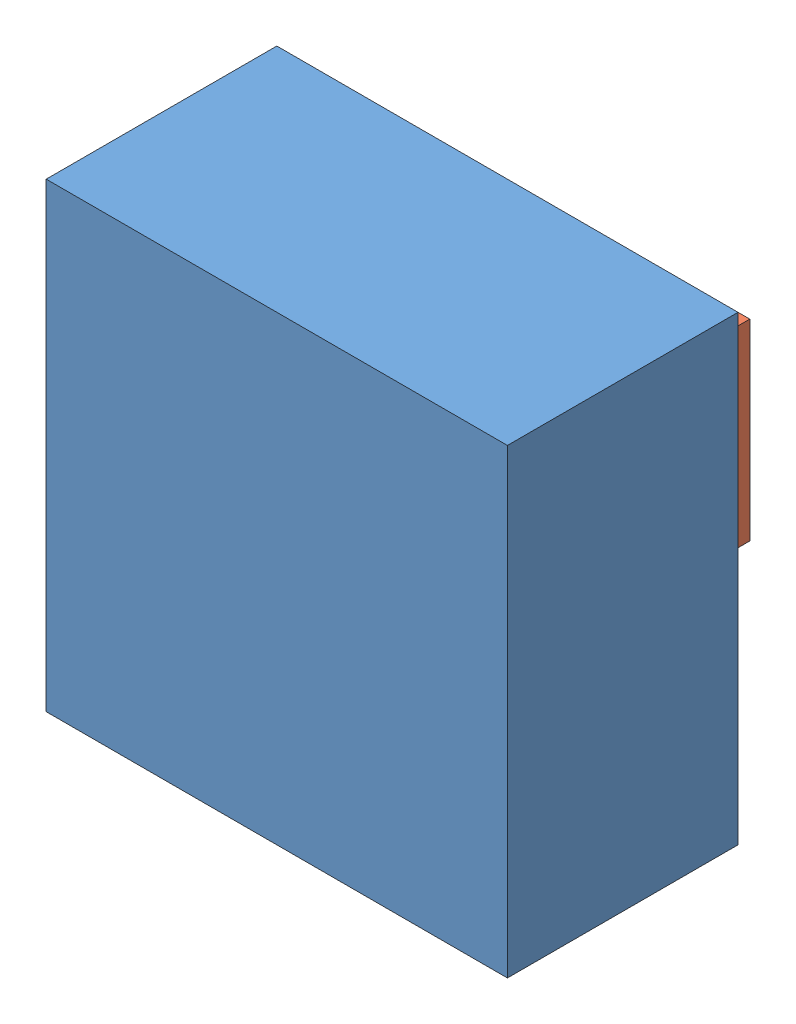
SolidWorks assembly peg hole 0, configuration Default. Lengths in mm.
Overall size (120 120 100).
2 component instances, 2 part files, 2 mates.
Components (placement in the parent):
- cubehole-1: cubehole [Default] at (39.9362 66.0398 73.4279) size (120 120 60)
- cube peg-1: cube peg [Default] at (50.358 44.4564 33.4279) x (0 -1 0) z (0 0 1) size (50 50 90)
Mates (geometry in assembly coordinates):
- 重合4: coincident anti-aligned: plane of cubehole-1 through (39.9362 66.0398 123.4279) normal (0 0 -1); plane of cube peg-1 through (50.358 44.4564 123.4279) normal (0 0 1)
- 重合5: coincident anti-aligned: plane of cubehole-1 through (19.6354 24.7804 123.4279) normal (0 1 0); plane of cube peg-1 through (72.696 24.7804 123.4279) normal (0 -1 0)
